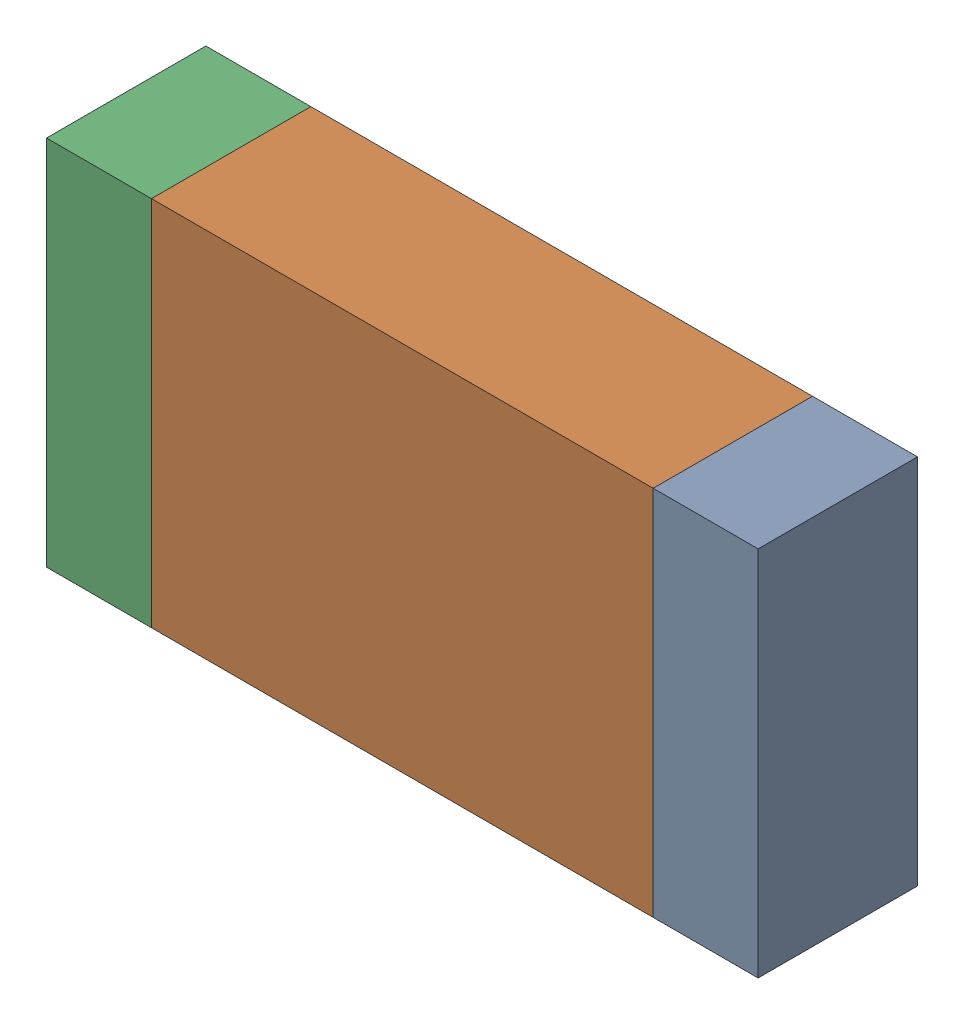
SolidWorks assembly R01-1, configuration Default. Lengths in mm.
Overall size (3.35 1.75 0.75).
6 component instances, 2 part files, 0 mates.
Components (placement in the parent):
- 959206760-1-1: 959206760-1 [Default] at (117.3285 91.9479 0) size (0.49 1.75 0.75)
  - Extruded-33-1: Extruded-33 [Default] at origin size (0.49 1.75 0.75)
- 959206896-1-1: 959206896-1 [Default] at (115.901 91.9479 0) size (2.36 1.75 0.75)
  - Extruded-34-1: Extruded-34 [Default] at origin size (2.36 1.75 0.75)
- 959206760-1-2: 959206760-1 [Default] at (114.4735 91.9479 0) size (0.49 1.75 0.75)
  - Extruded-33-1: Extruded-33 [Default] at origin size (0.49 1.75 0.75)
